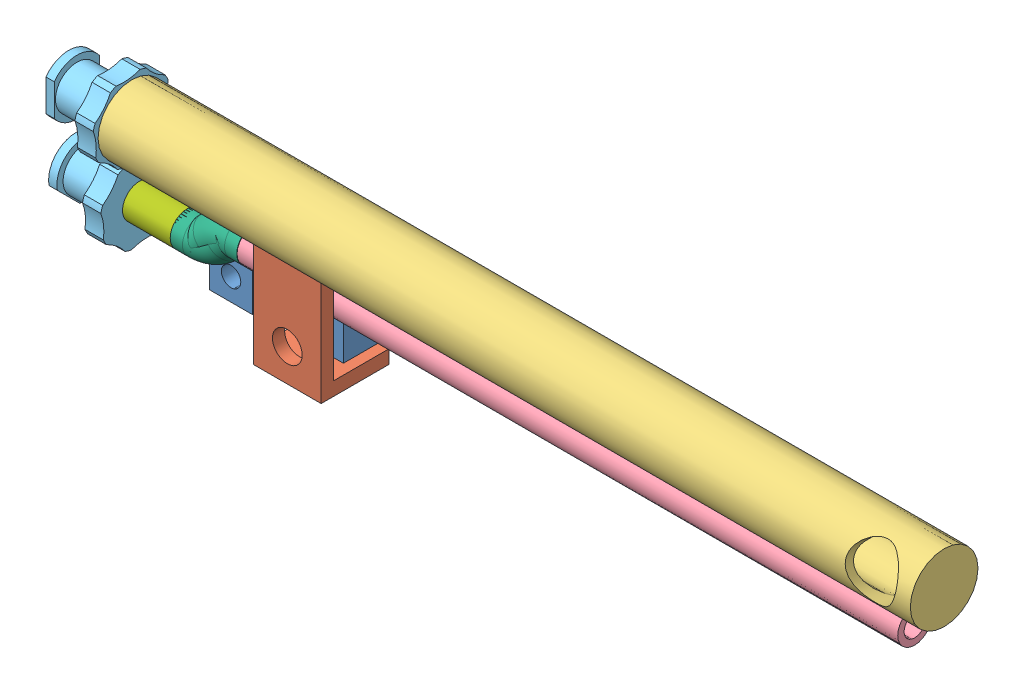
SolidWorks assembly tube holder assem, configuration Default. Lengths in mm.
Overall size (82.13 15.87 10.25).
10 component instances, 7 part files, 4 mates.
Components (placement in the parent):
- tube holder-1: tube holder [Default] at (2.0924 2.1909 -3.1299) size (12.57 9.53 4)
- tube clip-1: tube clip [Default] at (6.1681 -3.5321 0.7457) x (-1 -0.000016 0) z (0 0 -1) size (6.35 11.43 6.35)
- tube assem-2: tube assem [Default] at (65.772 8.7165 1.9056) x (0 0 -1) z (-1 0 0) size (10.25 15.76 82.13)
  - long tube-1: long tube [Default] x (-1 0 0) z (0 0 1) size (6.35 6.35 76.2)
  - short tube-1: short tube [Default] at (0.7155 5.1856 65.4617) x (0.872865 -0.487962 0) z (0 0 -1) size (3.17 3.17 61.98)
  - LUER LOCK-3: LUER LOCK [Default] at (0 0 65.6348) size (7.25 7.25 12.43)
  - LUER LOCK-4: LUER LOCK [Default] at (0.7123 7.0161 65.6348) x (0.707107 -0.707107 0) z (0 0 1) size (7.25 7.25 12.43)
  - 1946K240_MARINE-RATED COPPER-NICKEL PIPE FITTING-1: 1946K240_MARINE-RATED COPPER-NICKEL PIPE FITTING [1946K24] at (0.7123 10.6533 67.5596) x (-1 0 0) z (0 -0.707107 0.707107) size (3.18 5.73 4.6)
  - 1946K240_MARINE-RATED COPPER-NICKEL PIPE FITTING-2: 1946K240_MARINE-RATED COPPER-NICKEL PIPE FITTING [1946K24] at (0.7155 1.5483 69.6519) x (-1 0 0) z (0 0.707107 -0.707107) size (3.18 5.73 4.6)
  - tube small-1: tube small [Default] at (0.7123 7.0161 70.612) size (3.17 3.17 5.59)
Mates (geometry in assembly coordinates):
- Concentric5: concentric aligned: circle of tube holder-1; circle of tube clip-1
- Tangent1: tangent anti-aligned: plane of tube holder-1 through (8.3784 3.5309 -1.0549) normal (0 0.707107 0.707107); cylinder of tube assem-2/short tube-1 through (62.2864 3.5309 1.1902) axis (-1 0 0) radius 1.5875
- Tangent2: tangent anti-aligned: plane of tube holder-1 through (8.3784 5.4559 0.8701) normal (0 -0.707107 0.707107); cylinder of tube assem-2/short tube-1 through (62.2864 3.5309 1.1902) axis (-1 0 0) radius 1.5875
- Tangent3: tangent anti-aligned: plane of tube clip-1 through (9.3429 7.898 2.7777) normal (0 0 -1); cylinder of tube assem-2/short tube-1 through (62.2864 3.5309 1.1902) axis (-1 0 0) radius 1.5875
